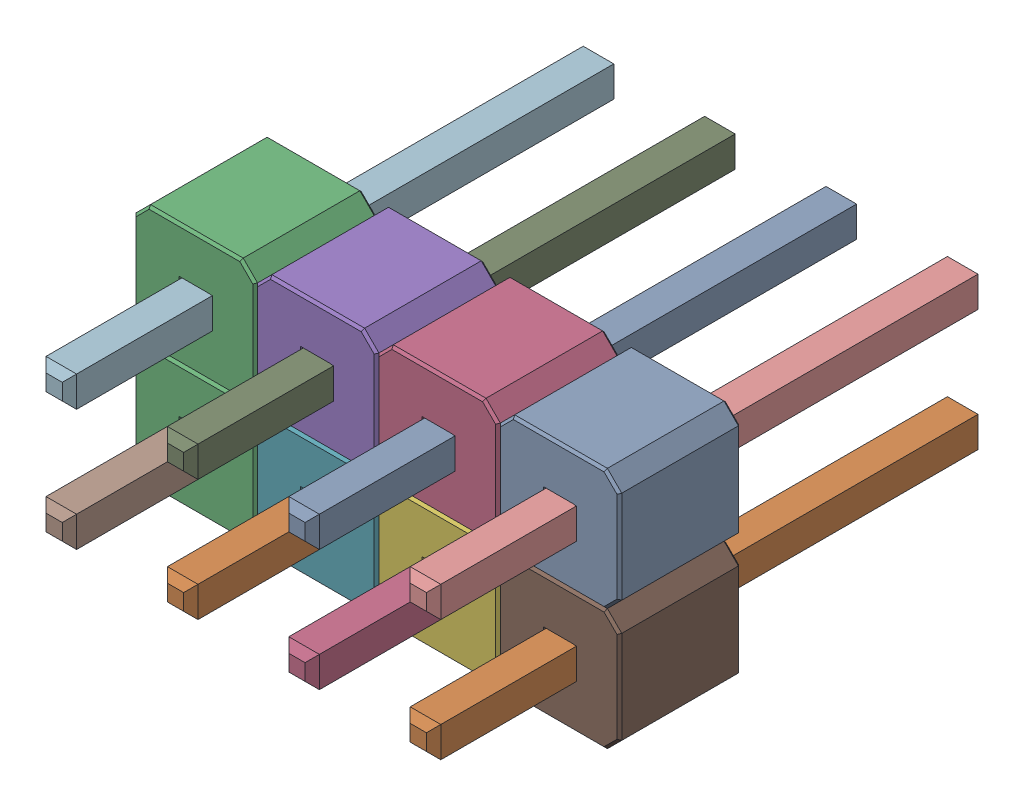
SolidWorks assembly X1_XLR3, configuration Default. Lengths in mm.
Overall size (10.16 5.08 11.54).
17 component instances, 2 part files, 0 mates.
Components (placement in the parent):
- PLD-8-1: PLD-8 [Default] at (79.5021 88.1379 -1.2114) x (1 0 0) z (0 0 -1) size (10.16 5.08 11.54)
  - _______________________-1: _______________________ [Default] at (-2.54 0 -3) size (0.64 0.64 11.54)
  - _______________________-2: _______________________ [Default] at (-5.08 2.54 -3) size (0.64 0.64 11.54)
  - _________-1: _________ [Default] at (-7.6724 2.5342 -0.0112) size (2.54 2.54 2.54)
  - _______________________-3: _______________________ [Default] at (-2.54 2.54 -3) size (0.64 0.64 11.54)
  - _________-2: _________ [Default] at (-5.1324 -0.0058 -0.0112) size (2.54 2.54 2.54)
  - _________-3: _________ [Default] at (-2.5924 2.5342 -0.0112) size (2.54 2.54 2.54)
  - _________-4: _________ [Default] at (-5.1324 2.5342 -0.0112) size (2.54 2.54 2.54)
  - _______________________-4: _______________________ [Default] at (-7.62 2.54 -3) size (0.64 0.64 11.54)
  - _______________________-5: _______________________ [Default] at (-5.08 0 -3) size (0.64 0.64 11.54)
  - _______________________-6: _______________________ [Default] at (0 0 -3) size (0.64 0.64 11.54)
  - _________-5: _________ [Default] at (-0.0524 2.5342 -0.0112) size (2.54 2.54 2.54)
  - _______________________-7: _______________________ [Default] at (-7.62 0 -3) size (0.64 0.64 11.54)
  - _________-6: _________ [Default] at (-0.0524 -0.0058 -0.0112) size (2.54 2.54 2.54)
  - _______________________-8: _______________________ [Default] at (0 2.54 -3) size (0.64 0.64 11.54)
  - _________-7: _________ [Default] at (-7.6724 -0.0058 -0.0112) size (2.54 2.54 2.54)
  - _________-8: _________ [Default] at (-2.5924 -0.0058 -0.0112) size (2.54 2.54 2.54)
